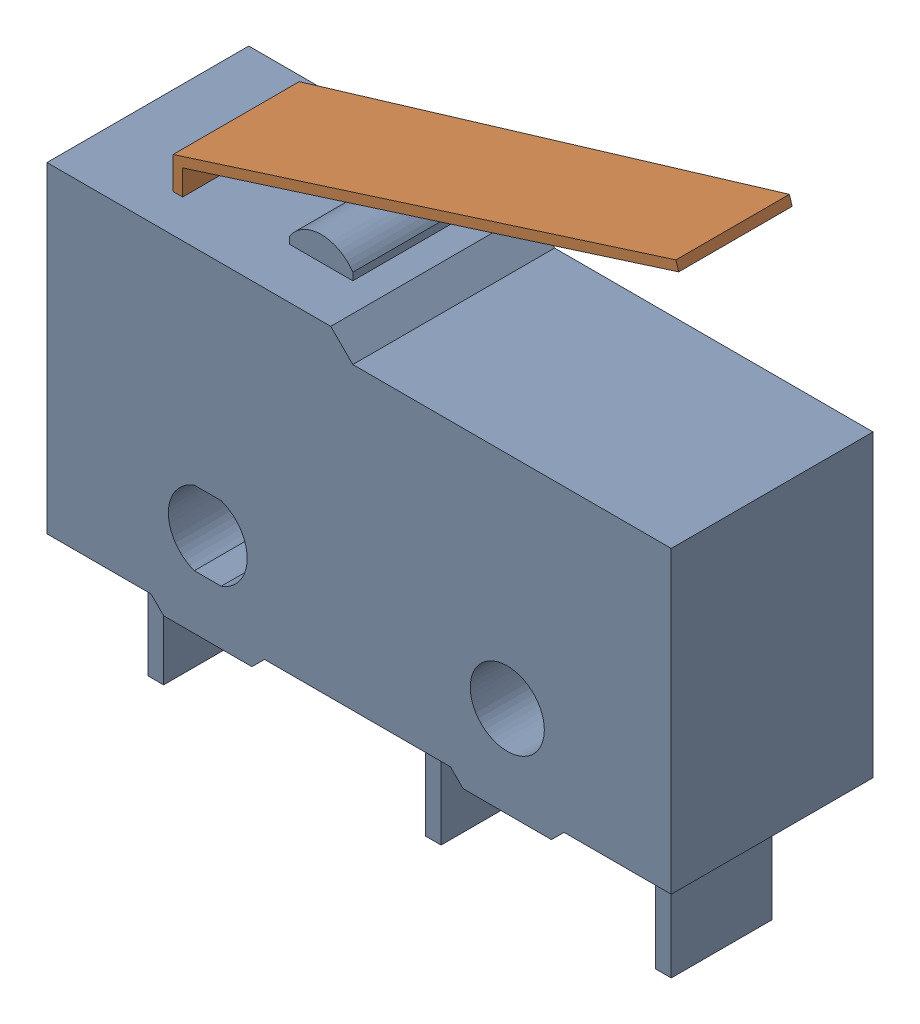
SolidWorks assembly OMRON_ss-5gl, configuration Default. Lengths in mm.
Overall size (19.8 20 6.4).
2 component instances, 2 part files, 1 mates.
Components (placement in the parent):
- SS_01GL_E_BASE-1: SS_01GL_E_BASE [Default] at origin size (19.8 14.87 6.4)
- SS_01GL_E_ACTUATOR-1: SS_01GL_E_ACTUATOR [Default] at (-11.5 7.7 0) size (15.84 5.9 4)
Mates (geometry in assembly coordinates):
- Distance4: distance = 13.6 mm: plane of SS_01GL_E_BASE-1; line of SS_01GL_E_ACTUATOR-1 through (3.9483 13.6 1.8) axis (0 0 -1)
